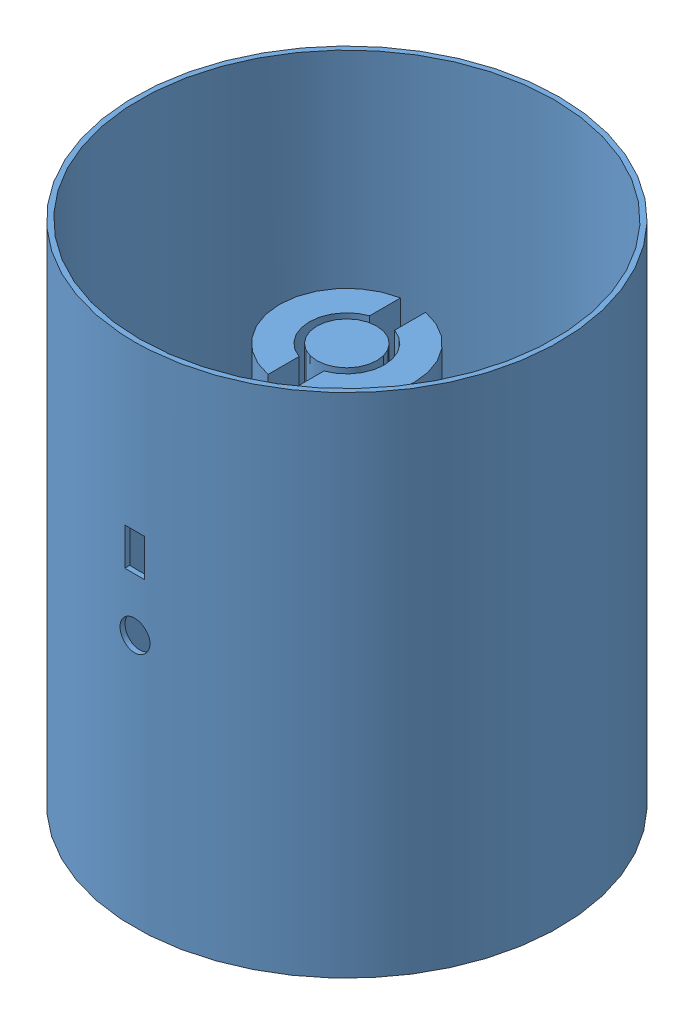
SolidWorks assembly socle pour fab, configuration Défaut. Lengths in mm.
Overall size (170 203 170).
17 component instances, 8 part files, 21 mates.
Components (placement in the parent):
- socle + batterir-1: socle + batterir [Défaut] at (-21.7162 -113.9782 281.9036) size (170 203 170)
- tablette dessous cache batterie 2-1: tablette dessous cache batterie 2 [Défaut] at (-21.7162 80.0218 281.9036) x (-0.604559 0 0.79656) z (-0.79656 0 -0.604559) size (166 5 87.6) (hidden)
- tablette dessus cache batterie-1: tablette dessus cache batterie [Défaut] at (-21.7162 93.0218 281.9036) x (0.520422 0 -0.853909) z (-0.853909 0 -0.520422) size (172 8.11 90.98) (hidden)
- assemblage roulette-1: assemblage roulette [Défaut] at (-73.4979 -112.9832 278.1532) size (35 29.34 35) (hidden)
  - roulette corps-1: roulette corps [Défaut] at (-2.1553 -2.495 35) size (35 16.51 35) (hidden)
  - roulette bille-1: roulette bille [Défaut] at (-2.1553 -2.495 35) x (0.662663 0.734724 0.145116) z (-0.48632 0.274797 0.829445) size (18 18 18) (hidden)
- assemblage roulette-2: assemblage roulette [Défaut] at (0.9267 -112.9832 328.6231) x (-0.5 0 -0.866025) z (0.866025 0 -0.5) size (35 29.34 35)
  - roulette corps-1: roulette corps [Défaut] at (-2.1553 -2.495 35) size (35 16.51 35) (hidden)
  - roulette bille-1: roulette bille [Défaut] at (-2.1553 -2.495 35) x (0.662663 0.734724 0.145116) z (-0.48632 0.274797 0.829445) size (18 18 18) (hidden)
- assemblage roulette-3: assemblage roulette [Défaut] at (7.4226 -112.9832 238.9345) x (-0.5 0 0.866025) z (-0.866025 0 -0.5) size (35 29.34 35)
  - roulette corps-1: roulette corps [Défaut] at (-2.1553 -2.495 35) size (35 16.51 35) (hidden)
  - roulette bille-1: roulette bille [Défaut] at (-2.1553 -2.495 35) x (0.662663 0.734724 0.145116) z (-0.48632 0.274797 0.829445) size (18 18 18) (hidden)
- mousse elec-1: mousse elec [Défaut] at (-21.7162 -53.9782 281.9036) x (-1 0 0) z (0 0 1) size (166 50 163.55) (hidden)
- batterie-1: batterie [Défaut] at (-70.76 -103.9782 279.7967) size (40 145 80) (hidden)
- boitier radio frequence-1: boitier radio frequence [Défaut] at (-24.1695 -103.9782 220.9615) x (0 0 1) z (-1 0 0) size (24 85 45) (hidden)
- boitier radio frequence-2: boitier radio frequence [Défaut] at (24.938 -103.9782 249.1382) x (-0.880578 0 0.473902) z (-0.473902 0 -0.880578) size (24 85 45) (hidden)
- boitier radio frequence-3: boitier radio frequence [Défaut] at (29.517 -103.9782 304.7504) x (-0.951342 0 -0.308136) z (0.308136 0 -0.951342) size (24 85 45) (hidden)
Mates (geometry in assembly coordinates):
- Coaxiale1: concentric aligned: cylinder of socle + batterir-1 through (-21.7162 89.0218 281.9036) axis (0 -1 0) radius 83; cylinder of tablette dessous cache batterie 2-1 through (-21.7162 85.0218 281.9036) axis (0 -1 0) radius 83
- Coïncidente1: coincident anti-aligned: circle of socle + batterir-1; plane of tablette dessous cache batterie 2-1 through (-21.7162 80.0218 281.9036) normal (0 -1 0)
- Coaxiale3: concentric anti-aligned: cylinder of socle + batterir-1 through (-21.7162 89.0218 281.9036) axis (0 -1 0) radius 83; cylinder of tablette dessus cache batterie-1 through (-21.7162 85.0218 281.9036) axis (0 1 0) radius 83
- Coïncidente2: coincident anti-aligned: plane of socle + batterir-1 through (-21.7162 89.0218 281.9036) normal (0 1 0); plane of tablette dessus cache batterie-1 through (-21.7162 89.0218 281.9036) normal (0 -1 0)
- Coïncidente4: coincident anti-aligned: plane of socle + batterir-1 through (-21.7162 -113.9782 281.9036) normal (0 -1 0); plane of assemblage roulette-1/roulette corps-1 through (-75.6532 -113.9782 313.1532) normal (0 1 0)
- Coaxiale4: concentric anti-aligned: cylinder of socle + batterir-1 through (-21.7162 46.0218 281.9036) axis (0 -1 0) radius 27; cylinder of mousse elec-1 through (-21.7162 -103.9782 281.9036) axis (0 1 0) radius 30
- Coïncidente7: coincident anti-aligned: plane of socle + batterir-1 through (-21.7162 -103.9782 281.9036) normal (0 1 0); plane of mousse elec-1 through (-21.7162 -103.9782 281.9036) normal (0 -1 0)
- Coïncidente8: coincident anti-aligned: plane of socle + batterir-1 through (-1.7162 -103.9782 322.4579) normal (1 0 0); plane of mousse elec-1 through (-1.7162 -103.9782 281.9036) normal (-1 0 0)
- Coïncidente9: coincident anti-aligned: plane of socle + batterir-1 through (-21.7162 -103.9782 281.9036) normal (0 1 0); plane of batterie-1 through (-70.76 -103.9782 279.7967) normal (0 -1 0)
- Coïncidente10: coincident anti-aligned: plane of mousse elec-1 through (-50.76 -103.9782 281.9036) normal (-1 0 0); plane of batterie-1 through (-50.76 36.0218 239.7967) normal (1 0 0)
- Coïncidente11: coincident anti-aligned: plane of mousse elec-1 through (-21.7162 -103.9782 319.7967) normal (0 0 -1); plane of batterie-1 through (-90.76 36.0218 319.7967) normal (0 0 1)
- Coïncidente12: coincident anti-aligned: plane of socle + batterir-1 through (-21.7162 -103.9782 281.9036) normal (0 1 0); plane of boitier radio frequence-1 through (-24.1695 -103.9782 220.9615) normal (0 -1 0)
- Coïncidente13: coincident anti-aligned: plane of mousse elec-1 through (-21.7162 -103.9782 232.9615) normal (0 0 -1); plane of boitier radio frequence-1 through (-1.6695 -18.9782 232.9615) normal (0 0 1)
- Coïncidente14: coincident anti-aligned: plane of mousse elec-1 through (-1.6695 -103.9782 281.9036) normal (-1 0 0); plane of boitier radio frequence-1 through (-1.6695 -18.9782 208.9615) normal (1 0 0)
- Coïncidente15: coincident anti-aligned: plane of socle + batterir-1 through (-21.7162 -103.9782 281.9036) normal (0 1 0); plane of boitier radio frequence-2 through (24.938 -103.9782 249.1382) normal (0 -1 0)
- Coïncidente17: coincident: plane of mousse elec-1 through (17.5666 -103.9782 260.7627) normal (0.880578 0 -0.473902); line of boitier radio frequence-2 through (7.0256 -18.9782 241.1761) axis (0.473902 0 0.880578)
- Parallèle1: parallel anti-aligned: plane of boitier radio frequence-2 through (24.8422 -18.9782 223.6384) normal (-0.473902 0 -0.880578); plane of mousse elec-1 through (-35.5745 -103.9782 256.1529) normal (0.473902 0 0.880578)
- Coïncidente19: coincident anti-aligned: plane of mousse elec-1 through (-14.2489 -103.9782 295.7789) normal (-0.473902 0 -0.880578); plane of boitier radio frequence-2 through (46.1678 -18.9782 263.2644) normal (0.473902 0 0.880578)
- Coïncidente20: coincident anti-aligned: plane of socle + batterir-1 through (-21.7162 -103.9782 281.9036) normal (0 1 0); plane of boitier radio frequence-3 through (29.517 -103.9782 304.7504) normal (0 -1 0)
- Coïncidente21: coincident anti-aligned: plane of mousse elec-1 through (-30.4821 -103.9782 308.9677) normal (0.308136 0 -0.951342); plane of boitier radio frequence-3 through (34 -18.9782 329.8532) normal (-0.308136 0 0.951342)
- Coïncidente22: coincident anti-aligned: plane of mousse elec-1 through (19.9337 -103.9782 295.3938) normal (0.951342 0 0.308136); plane of boitier radio frequence-3 through (11.1678 -18.9782 322.4579) normal (-0.951342 0 -0.308136)
